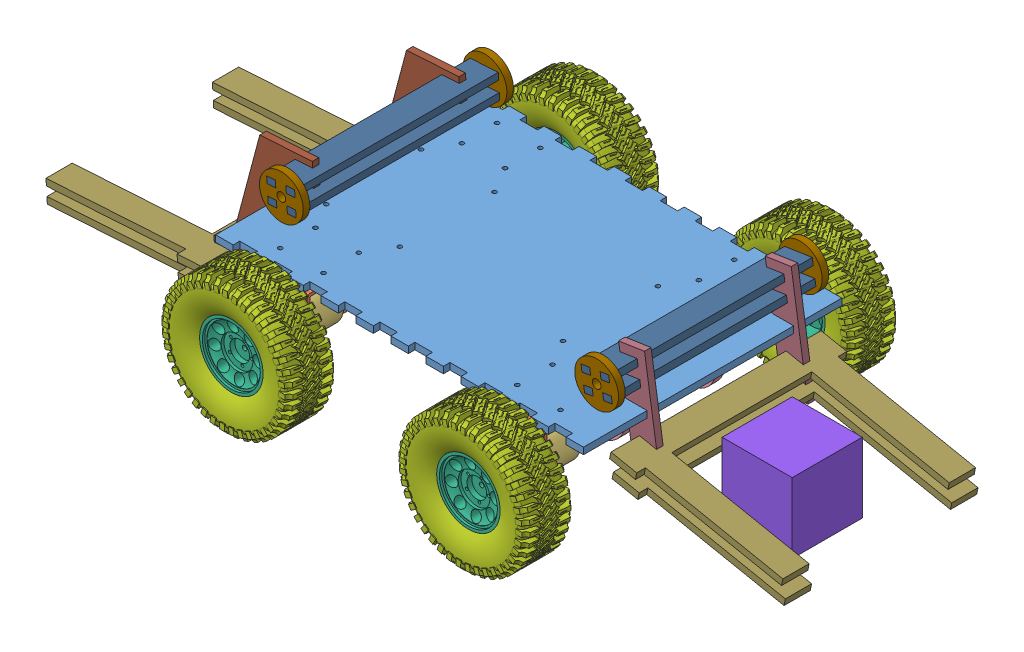
SolidWorks assembly RobotAssembly, configuration Default. Lengths in mm.
Overall size (538.8 153.4 271.4).
48 component instances, 13 part files, 10 mates.
Components (placement in the parent):
- Chassis-1: Chassis [Default] at origin size (266.7 4.76 187.32)
- MotorAssembly-4: MotorAssembly [Default] at (222.3107 -16.5734 66.5129) x (0 0 1) z (1 0 0) size (109.89 133.47 133.47) (flexible)
  - FrontMotorSupport-1: FrontMotorSupport [Default] at (25.1496 -16.5734 -2.9307) size (51.5 39.6 37.5)
  - Motor-1: Motor [Default] at (25.1496 4.2766 -2.9307) x (0 0 -1) z (1 0 0) size (36.8 36.8 85.85)
  - BackMotorSupport-1: BackMotorSupport [Default] at (-33.7154 -16.5734 -2.9307) size (9.52 41.17 63.5)
  - MotorShaftMount-1: MotorShaftMount [Default] at (51.2964 12.7766 -2.9307) x (0 -0.871442 0.490499) z (-1 0 0) size (13.86 12 18.15)
  - Rim-1: Rim [Default] at (45.1484 12.7766 -2.9307) x (1 0 0) z (0 0.860506 0.509441) size (24 46 46)
  - Tire-1: Tire [Default] at (51.2984 12.7766 -2.9307) x (1 0 0) z (0 0.596426 0.802668) size (35.57 95.4 95.4)
- MotorAssembly-5: MotorAssembly [Default] at (50.4307 -16.5734 66.5129) x (0 0 1) z (1 0 0) size (109.89 95.4 95.4) (flexible)
  - FrontMotorSupport-1: FrontMotorSupport [Default] at (25.1496 -16.5734 -2.9307) size (51.5 39.6 37.5)
  - Motor-1: Motor [Default] at (25.1496 4.2766 -2.9307) x (0 0 -1) z (1 0 0) size (36.8 36.8 85.85)
  - BackMotorSupport-1: BackMotorSupport [Default] at (-33.7154 -16.5734 -2.9307) size (9.52 41.17 63.5)
  - MotorShaftMount-1: MotorShaftMount [Default] at (51.2964 12.7766 -2.9307) x (0 -0.877703 0.479206) z (-1 0 0) size (13.86 12 18.15)
  - Rim-1: Rim [Default] at (45.1484 12.7766 -2.9307) x (1 0 0) z (0 0.853856 0.52051) size (24 46 46)
  - Tire-1: Tire [Default] at (51.2984 12.7766 -2.9307) size (35.57 95.4 95.4)
- MotorAssembly-6: MotorAssembly [Default] at (216.4493 -16.5734 -66.5129) x (0 0 -1) z (-1 0 0) size (109.89 133.47 133.47) (flexible)
  - FrontMotorSupport-1: FrontMotorSupport [Default] at (25.1496 -16.5734 -2.9307) size (51.5 39.6 37.5)
  - Motor-1: Motor [Default] at (25.1496 4.2766 -2.9307) x (0 0 -1) z (1 0 0) size (36.8 36.8 85.85)
  - BackMotorSupport-1: BackMotorSupport [Default] at (-33.7154 -16.5734 -2.9307) size (9.52 41.17 63.5)
  - MotorShaftMount-1: MotorShaftMount [Default] at (51.2964 12.7766 -2.9307) x (0 -0.871442 0.490499) z (-1 0 0) size (13.86 12 18.15)
  - Rim-1: Rim [Default] at (45.1484 12.7766 -2.9307) x (1 0 0) z (0 0.860506 0.509441) size (24 46 46)
  - Tire-1: Tire [Default] at (51.2984 12.7766 -2.9307) x (1 0 0) z (0 0.596426 0.802668) size (35.57 95.4 95.4)
- MotorAssembly-7: MotorAssembly [Default] at (44.5693 -16.5734 -66.5129) x (0 0 -1) z (-1 0 0) size (109.89 95.4 95.4) (flexible)
  - FrontMotorSupport-1: FrontMotorSupport [Default] at (25.1496 -16.5734 -2.9307) size (51.5 39.6 37.5)
  - Motor-1: Motor [Default] at (25.1496 4.2766 -2.9307) x (0 0 -1) z (1 0 0) size (36.8 36.8 85.85)
  - BackMotorSupport-1: BackMotorSupport [Default] at (-33.7154 -16.5734 -2.9307) size (9.52 41.17 63.5)
  - MotorShaftMount-1: MotorShaftMount [Default] at (51.2964 12.7766 -2.9307) x (0 -0.877703 0.479206) z (-1 0 0) size (13.86 12 18.15)
  - Rim-1: Rim [Default] at (45.1484 12.7766 -2.9307) x (1 0 0) z (0 0.853856 0.52051) size (24 46 46)
  - Tire-1: Tire [Default] at (51.2984 12.7766 -2.9307) size (35.57 95.4 95.4)
- Cube Hollow-1: Cube Hollow [Default] at (282.436 -74.295 8.8844) size (50.8 50.8 50.8)
- ChopsticksAssembly-1: ChopsticksAssembly [Default] at (25.4 30.1625 -80.9625) x (0 0 1) z (0.061682 -0.998096 0) size (152.4 197.48 104.78)
  - ChopstickServoMount-1: ChopstickServoMount [Default] at origin size (4.76 31.75 31.75)
  - ChopstickCam-2: ChopstickCam [Default] at (0 -10.16 -8.5725) size (152.4 20.32 4.76)
  - ChopstickCam-3: ChopstickCam [Default] at (0 -10.16 3.81) size (152.4 20.32 4.76)
  - ChopstickServoMount-2: ChopstickServoMount [Default] at (147.6375 0 0) size (4.76 31.75 31.75)
  - ChopstickLower-1: ChopstickLower [Default] at (131.7625 -2.54 -12.7) x (-1 0 0) z (0 -1 0) size (4.76 101.6 76.2)
  - ChopstickLower-2: ChopstickLower [Default] at (25.4 -2.54 -12.7) x (-1 0 0) z (0 -1 0) size (4.76 101.6 76.2)
  - Chopsticks-1: Chopsticks [Default] at (76.2 60.96 68.8975) x (1 0 0) z (0 -1 0) size (152.4 4.76 120.65)
  - Chopsticks-2: Chopsticks [Default] at (76.2 60.96 80.01) x (1 0 0) z (0 -1 0) size (152.4 4.76 120.65)
- ChopsticksAssembly2-1: ChopsticksAssembly2 [Default] at (250.825 23.8125 68.2625) x (0 0 -1) z (0.150975 -0.988538 0) size (152.4 133.82 112.12)
  - ChopstickServoMount-1: ChopstickServoMount [Default] at origin size (4.76 31.75 31.75)
  - ChopstickCam-2: ChopstickCam [Default] at (0 -10.16 -8.5725) size (152.4 20.32 4.76)
  - ChopstickCam-3: ChopstickCam [Default] at (0 -10.16 3.81) size (152.4 20.32 4.76)
  - ChopstickServoMount-2: ChopstickServoMount [Default] at (147.6375 0 0) size (4.76 31.75 31.75)
  - Chopsticks-1: Chopsticks [Default] at (76.2 4.5759 38.6772) x (1 0 0) z (0 -0.939693 -0.34202) size (152.4 4.76 120.65)
  - Chopsticks-2: Chopsticks [Default] at (76.2 4.5759 50.5029) x (1 0 0) z (0 -0.939693 -0.34202) size (152.4 4.76 120.65)
  - ChopstickLower2-1: ChopstickLower2 [Default] at (25.4 -2.54 0) x (0 1 0) z (-1 0 0) size (19.05 81.19 4.76)
  - ChopstickLower2-2: ChopstickLower2 [Default] at (131.7625 -2.54 0) x (0 1 0) z (-1 0 0) size (19.05 81.19 4.76)
Mates (geometry in assembly coordinates):
- Coincident11: coincident anti-aligned: plane of Chassis-1 through (0 0 0) normal (0 -1 0); plane of MotorAssembly-4/FrontMotorSupport-1 through (219.38 0 93.6625) normal (0 1 0)
- Concentric23: concentric aligned: cylinder of Chassis-1 through (203.63 0 78.6125) axis (0 1 0) radius 1.5; cylinder of MotorAssembly-4/FrontMotorSupport-1 through (203.63 -2 78.6125) axis (0 1 0) radius 1.6
- Concentric24: concentric aligned: cylinder of Chassis-1 through (203.63 0 53.0625) axis (0 1 0) radius 1.5; cylinder of MotorAssembly-4/FrontMotorSupport-1 through (203.63 -2 53.0625) axis (0 1 0) radius 1.6
- Coincident14: coincident aligned: plane of Cube Hollow-1 through (282.436 -74.295 8.8844) normal (0 -1 0)
- Distance4: distance = 25.4 mm: cylinder of ChopsticksAssembly-1/ChopstickServoMount-1 through (25.4 30.1625 -76.2) axis (0 0 -1) radius 15.875; plane of Chassis-1 through (0 4.7625 0) normal (0 1 0)
- Distance5: distance = 25.4 mm: cylinder of ChopsticksAssembly-1/ChopstickServoMount-1 through (25.4 30.1625 -76.2) axis (0 0 -1) radius 15.875; plane of Chassis-1 through (0 4.7625 0) normal (-1 0 0)
- Distance6: distance = 12.7 mm aligned: plane of Chassis-1 through (0 4.7625 -93.6625) normal (0 0 -1); plane of ChopsticksAssembly-1/ChopstickServoMount-1 through (25.4 30.1625 -80.9625) normal (0 0 -1)
- Distance11: distance = 25.4 mm aligned: plane of ChopsticksAssembly2-1/ChopstickServoMount-1 through (250.825 23.8125 68.2625) normal (0 0 1); plane of Chassis-1 through (0 4.7625 93.6625) normal (0 0 1)
- Tangent3: tangent aligned: plane of Chassis-1 through (266.7 4.7625 0) normal (1 0 0); cylinder of ChopsticksAssembly2-1/ChopstickServoMount-1 through (250.825 23.8125 63.5) axis (0 0 1) radius 15.875
- Distance12: distance = 19.05 mm: cylinder of ChopsticksAssembly2-1/ChopstickServoMount-1 through (250.825 23.8125 63.5) axis (0 0 1) radius 15.875; plane of Chassis-1 through (0 4.7625 0) normal (0 1 0)
